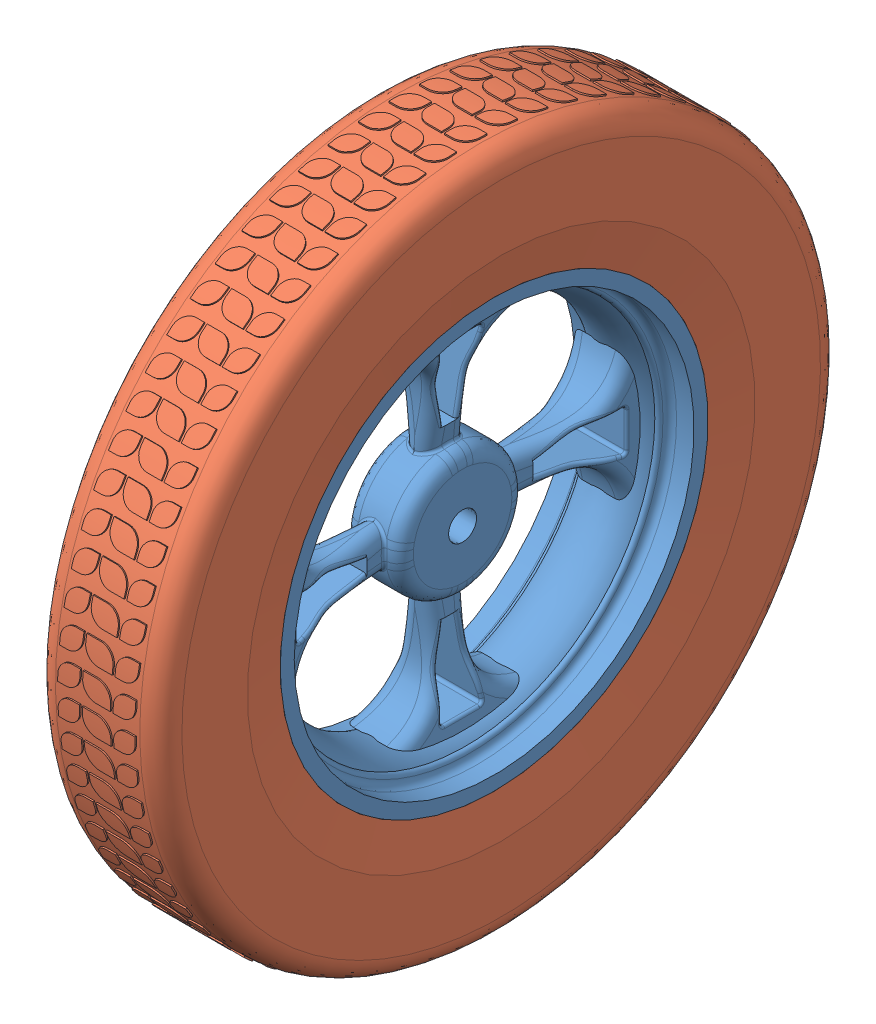
SolidWorks assembly Ensamblaje4, configuration Predeterminado. Lengths in mm.
Overall size (90 486.8 486.8).
2 component instances, 2 part files, 2 mates.
Components (placement in the parent):
- llanta-1: llanta [Predeterminado] at (-35.6202 19.6316 304.8) size (85 304.8 304.8)
- Tyre-2: Tyre [Predeterminado] at (-33.1202 -177.7684 304.8) x (1 0 0) z (0 1 0) size (90 486.8 486.8)
Mates (geometry in assembly coordinates):
- Coincidente1: coincident: circle of llanta-1; circle of Tyre-2
- Coincidente3: coincident anti-aligned: plane of llanta-1 through (-35.6202 19.6316 304.8) normal (0 0 1); plane of Tyre-2 through (-33.1202 -177.7684 304.8) normal (0 0 -1)
